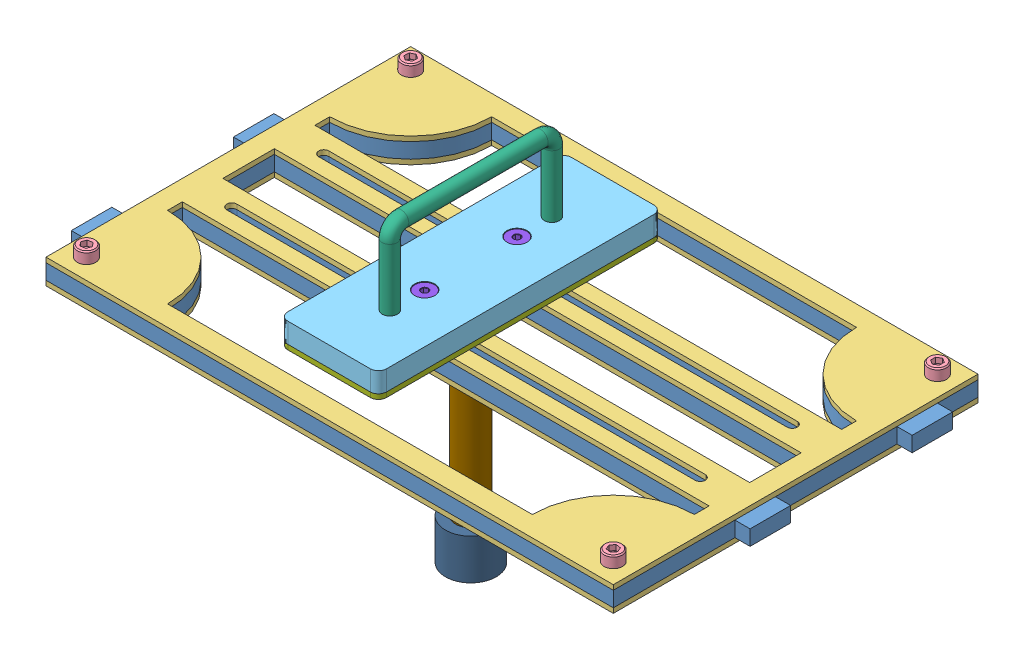
SolidWorks assembly Killswitch4, configuration Default. Lengths in mm.
Overall size (187.33 106.62 114.3).
23 component instances, 11 part files, 39 mates.
Components (placement in the parent):
- Panel-2: Panel [Default] at origin size (187.33 4.76 114.3)
- Magnet-1: Magnet [Default] at (73.406 2.3813 39.37) size (4.76 4.76 4.76)
- Magnet-2: Magnet [Default] at (73.406 2.3813 -39.37) size (4.76 4.76 4.76)
- Magnet-3: Magnet [Default] at (-73.406 2.3813 -39.37) size (4.76 4.76 4.76)
- Magnet-4: Magnet [Default] at (-73.406 2.3813 39.37) size (4.76 4.76 4.76)
- AcrylicPanel-1: AcrylicPanel [Default] at (0 4.7625 0) size (177.8 1.52 114.3)
- AcrylicPanel-2: AcrylicPanel [Default] at (0 -1.524 0) size (177.8 1.52 114.3)
- socket head cap screw_ai-2: socket head cap screw_ai [HX-SHCS 0.138-40x0.3125x0.3125-C] at (-82.55 9.7917 -50.8) x (0 -1 0) z (0.436855 0 0.899532) size (11.44 5.74 5.74)
- socket head cap screw_ai-3: socket head cap screw_ai [HX-SHCS 0.138-40x0.3125x0.3125-C] at (82.55 9.7917 -50.8) x (0 -1 0) z (-0.495278 0 0.868734) size (11.44 5.74 5.74)
- socket head cap screw_ai-4: socket head cap screw_ai [HX-SHCS 0.138-40x0.3125x0.3125-C] at (82.55 9.7917 50.8) x (0 -1 0) z (-0.933448 0 0.358714) size (11.44 5.74 5.74)
- socket head cap screw_ai-5: socket head cap screw_ai [HX-SHCS 0.138-40x0.3125x0.3125-C] at (-82.55 9.7917 50.8) x (0 -1 0) z (0.168939 0 0.985627) size (11.44 5.74 5.74)
- Slider-2: Slider [Default] at (-12.8947 12.573 -0.003) x (-1 0 0) z (0 0 1) size (30.96 6.29 88.9)
- Magnet-7: Magnet [Default] at (-12.8947 10.1917 -39.119) size (4.76 4.76 4.76)
- Magnet-8: Magnet [Default] at (-12.8947 10.1917 39.113) size (4.76 4.76 4.76)
- 1568A630-1: 1568A630 [1568A63] at (-12.8947 37.1158 -0.003) x (0 0 1) z (1 0 0) size (55.56 25.63 4.76)
- SliderAcrylic-1: SliderAcrylic [Default] at (-12.8947 6.2865 -0.003) size (30.96 1.52 88.9)
- socket head cap screw_ai-6: socket head cap screw_ai [HX-SHCS 0.112-40x0.4375x0.4375-C] at (-12.8947 3.4417 -25.403) x (0 1 0) z (0 0 1) size (13.96 4.65 4.65)
- socket head cap screw_ai-7: socket head cap screw_ai [HX-SHCS 0.112-40x0.4375x0.4375-C] at (-12.8947 3.4417 25.397) x (0 1 0) z (-0.253818 0 0.967252) size (13.96 4.65 4.65)
- 97345A428-3: 97345A428 [97345A428] at (-12.8947 10.795 14.475) size (6.35 20.18 6.35)
- 97345A428-4: 97345A428 [97345A428] at (-12.8947 10.795 -14.481) size (6.35 20.18 6.35)
- MagnetHolderB-1: MagnetHolderB [Default] at (-12.8947 -27.4955 -0.003) x (0.135705 0 0.990749) z (-0.990749 0 0.135705) size (9.53 76.2 9.53)
- MagnetCapAcrylic-1: MagnetCapAcrylic [Default] at (-12.8947 -67.1195 -0.003) x (0.50888 0 0.860837) z (-0.860837 0 0.50888) size (15.88 12.7 15.88)
- BigMagnet-1: BigMagnet [Default] at (-12.8947 -65.5955 -0.003) size (6.35 6.35 6.35)
Mates (geometry in assembly coordinates):
- Coincident1: coincident aligned: circle of Panel-2; circle of Magnet-1
- Coincident2: coincident aligned: circle of Panel-2; circle of Magnet-2
- Coincident3: coincident aligned: circle of Panel-2; circle of Magnet-4
- Coincident4: coincident aligned: circle of Panel-2; circle of Magnet-3
- Coincident5: coincident aligned: line of Panel-2 through (82.55 4.7625 -20.7675) axis (-1 0 0); line of AcrylicPanel-1 through (82.55 4.7625 -20.7675) axis (-1 0 0)
- Concentric1: concentric aligned: circle of Panel-2; circle of AcrylicPanel-1
- Coincident7: coincident aligned: line of Panel-2 through (82.55 0 -20.7675) axis (-1 0 0); line of AcrylicPanel-2 through (82.55 0 -20.7675) axis (-1 0 0)
- Concentric2: concentric aligned: circle of Panel-2; circle of AcrylicPanel-2
- Concentric81: concentric aligned: cylinder of Panel-2 through (-82.55 6.2865 -50.8) axis (0 1 0) radius 1.3526; cylinder of socket head cap screw_ai-2 through (-82.55 41.5417 -50.8) axis (0 1 0) radius 2.8702
- Concentric91: concentric aligned: cylinder of Panel-2 through (82.55 6.2865 -50.8) axis (0 1 0) radius 1.3526; cylinder of socket head cap screw_ai-3 through (82.55 41.5417 -50.8) axis (0 1 0) radius 2.8702
- Concentric101: concentric aligned: cylinder of Panel-2 through (82.55 6.2865 50.8) axis (0 1 0) radius 1.3526; cylinder of socket head cap screw_ai-4 through (82.55 41.5417 50.8) axis (0 1 0) radius 2.8702
- Concentric111: concentric aligned: cylinder of Panel-2 through (-82.55 6.2865 50.8) axis (0 1 0) radius 1.3526; cylinder of socket head cap screw_ai-5 through (-82.55 41.5417 50.8) axis (0 1 0) radius 2.8702
- Coincident25: coincident anti-aligned: plane of AcrylicPanel-1 through (-164.5488 6.2865 0) normal (0 1 0); plane of socket head cap screw_ai-5 through (-79.7211 6.2865 50.3151) normal (0 -1 0)
- Coincident26: coincident anti-aligned: plane of AcrylicPanel-1 through (-164.5488 6.2865 0) normal (0 1 0); plane of socket head cap screw_ai-2 through (-79.9682 6.2865 -52.0539) normal (0 -1 0)
- Coincident27: coincident anti-aligned: plane of AcrylicPanel-1 through (-164.5488 6.2865 0) normal (0 1 0); plane of socket head cap screw_ai-4 through (83.5796 6.2865 53.4792) normal (0 -1 0)
- Coincident28: coincident anti-aligned: plane of AcrylicPanel-1 through (-164.5488 6.2865 0) normal (0 1 0); plane of socket head cap screw_ai-3 through (85.0434 6.2865 -49.3785) normal (0 -1 0)
- Tangent1: tangent anti-aligned: plane of Panel-2 through (-73.406 0 -16.005) normal (0 0 1); cylinder of Slider-2 through (-12.8947 7.8105 -14.481) axis (0 1 0) radius 1.524
- Parallel1: parallel aligned: plane of Panel-2 through (-164.5488 4.7625 57.15) normal (0 0 1); plane of Slider-2 through (2.5834 7.8105 44.447) normal (0 0 1)
- Coincident36: coincident aligned: circle of Slider-2; circle of Magnet-7
- Coincident37: coincident aligned: circle of Slider-2; circle of Magnet-8
- Concentric13: concentric aligned: circle of Slider-2; circle of 1568A630-1
- Concentric14: concentric anti-aligned: circle of Slider-2; circle of 1568A630-1
- Coincident38: coincident anti-aligned: plane of Slider-2 through (-25.8329 14.097 -41.913) normal (0 1 0); plane of 1568A630-1 through (-12.8947 14.097 25.397) normal (0 -1 0)
- Coincident39: coincident anti-aligned: plane of Slider-2 through (-28.3729 7.8105 -44.453) normal (0 -1 0); plane of SliderAcrylic-1 through (2.5834 7.8105 -44.453) normal (0 1 0)
- Concentric15: concentric anti-aligned: circle of Slider-2; circle of SliderAcrylic-1
- Coincident41: coincident anti-aligned: plane of AcrylicPanel-1 through (-164.5488 6.2865 0) normal (0 1 0); plane of SliderAcrylic-1 through (2.5834 6.2865 -44.453) normal (0 -1 0)
- Concentric16: concentric aligned: circle of Slider-2; circle of socket head cap screw_ai-7
- Coincident44: coincident anti-aligned: plane of SliderAcrylic-1 through (2.5834 6.2865 -44.453) normal (0 -1 0); plane of socket head cap screw_ai-7 through (-15.1427 6.2865 24.8071) normal (0 1 0)
- Concentric17: concentric aligned: circle of Slider-2; circle of socket head cap screw_ai-6
- Coincident45: coincident anti-aligned: plane of SliderAcrylic-1 through (2.5834 6.2865 -44.453) normal (0 -1 0); plane of socket head cap screw_ai-6 through (-15.2188 6.2865 -25.403) normal (0 1 0)
- Concentric22: concentric aligned: circle of Slider-2; circle of 97345A428-3
- Coincident70: coincident anti-aligned: plane of Slider-2 through (-12.8947 10.795 14.475) normal (0 1 0); plane of 97345A428-3 through (-12.8947 10.795 14.475) normal (0 -1 0)
- Concentric23: concentric aligned: circle of Slider-2; circle of 97345A428-4
- Coincident71: coincident anti-aligned: plane of Slider-2 through (-12.8947 10.795 -14.481) normal (0 1 0); plane of 97345A428-4 through (-12.8947 10.795 -14.481) normal (0 -1 0)
- Concentric112: concentric anti-aligned: circle of Slider-2; circle of MagnetHolderB-1
- Coincident72: coincident anti-aligned: circle of Slider-2; plane of MagnetHolderB-1 through (-12.8947 10.6045 -0.003) normal (0 1 0)
- Concentric113: concentric aligned: circle of MagnetHolderB-1; circle of MagnetCapAcrylic-1
- Coincident76: coincident anti-aligned: plane of MagnetHolderB-1 through (-12.8947 -65.5955 -0.003) normal (0 -1 0); circle of MagnetCapAcrylic-1
- Coincident78: coincident anti-aligned: circle of MagnetHolderB-1; circle of BigMagnet-1
